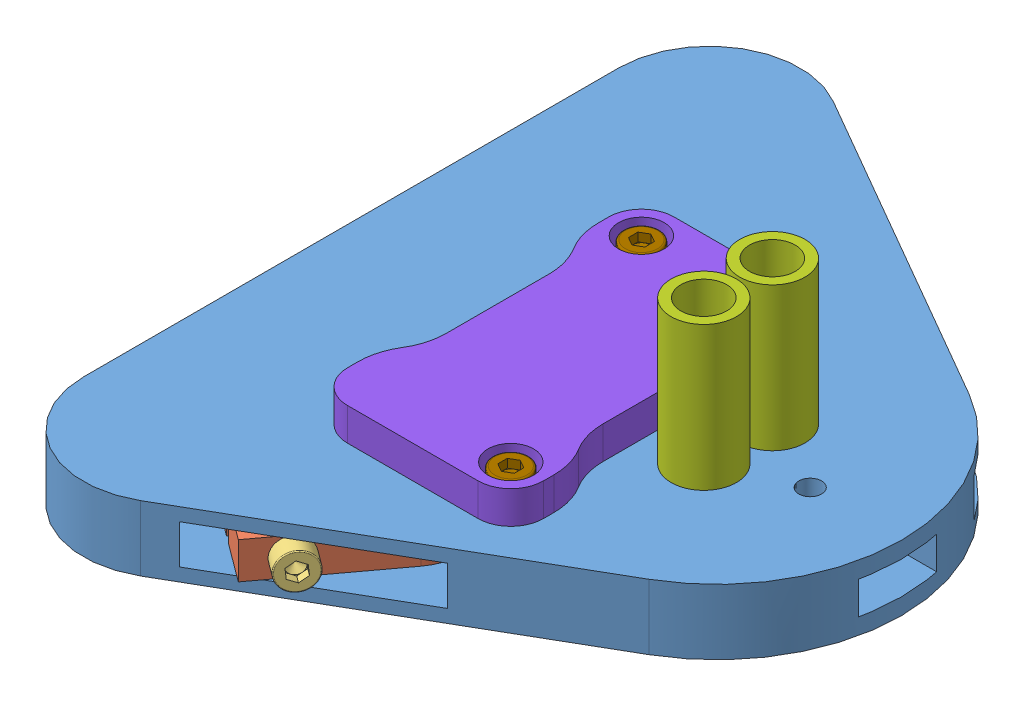
SolidWorks assembly PHeadAssembly, configuration Default. Lengths in mm.
Overall size (86.26 38.17 109.71).
26 component instances, 9 part files, 44 mates.
Components (placement in the parent):
- PHead-1: PHead [Default] at origin size (84.29 10 109.71)
- PRodFixAssembly-1: PRodFixAssembly [Default] at (15.0615 17.904 22.8104) x (-0.803549 0 -0.595239) z (-0.595239 0 0.803549) size (50.78 6 27.95)
  - PRodFix-1: PRodFix [Default] at (11.2747 15.304 14.188) size (15.9 5.6 27.95)
  - socket head cap screw_iso-2: socket head cap screw_iso [ISO 4762 M3 x 16 - 16N] at (0.3247 18.104 28.188) x (1 0 0) z (0 0.094972 0.99548) size (19 5.5 5.5)
  - hex nut style 1 gradeab_iso-3: hex nut style 1 gradeab_iso [ISO - 4032 - M3 - D - N] at (19.2247 18.104 28.188) x (0 -1 0) z (1 0 0) size (5.5 6.35 2.4)
- PRodFixAssembly-2: PRodFixAssembly [Default] at (46.5807 -17.904 -20.7975) x (-0.366111 0 0.930571) z (-0.930571 0 -0.366111) size (50.78 6 27.95)
  - PRodFix-1: PRodFix [Default] at (11.2747 15.304 14.188) size (15.9 5.6 27.95)
  - socket head cap screw_iso-2: socket head cap screw_iso [ISO 4762 M3 x 16 - 16N] at (0.3247 18.104 28.188) x (1 0 0) z (0 0.094972 0.99548) size (19 5.5 5.5)
  - hex nut style 1 gradeab_iso-3: hex nut style 1 gradeab_iso [ISO - 4032 - M3 - D - N] at (19.2247 18.104 28.188) x (0 -1 0) z (1 0 0) size (5.5 6.35 2.4)
- PRodFixAssembly-3: PRodFixAssembly [Default] at (-40.5758 -17.904 -32.9204) x (0.999782 0 0.02089) z (-0.02089 0 0.999782) size (50.78 6 27.95)
  - PRodFix-1: PRodFix [Default] at (11.2747 15.304 14.188) size (15.9 5.6 27.95)
  - socket head cap screw_iso-2: socket head cap screw_iso [ISO 4762 M3 x 16 - 16N] at (0.3247 18.104 28.188) x (1 0 0) z (0 0.094972 0.99548) size (19 5.5 5.5)
  - hex nut style 1 gradeab_iso-3: hex nut style 1 gradeab_iso [ISO - 4032 - M3 - D - N] at (19.2247 18.104 28.188) x (0 -1 0) z (1 0 0) size (5.5 6.35 2.4)
- _Riemenscheibe_GT2_20T-1: _Riemenscheibe_GT2_20T [Конфигурация1] at (0 0 -3.45) x (0 0 1) z (0.811645 0.584151 0) size (16 16 16)
- PHeadAchse-1: PHeadAchse [Default] at (0 0 -7.95) x (0 1 0) z (1 0 0) size (5 25 5)
- Kamerahalterung_Kabelführung_P-Kopf-1: Kamerahalterung_Kabelführung_P-Kopf [Standard] at (20 5 5) x (-0.29865 0 0.954363) z (-0.954363 0 -0.29865) size (10 22 10)
- hex nut style 1 gradeab_iso-2: hex nut style 1 gradeab_iso [ISO - 4032 - M3 - D - N] at (20 -4.9 5) x (0.5 0 -0.866025) z (0 -1 0) size (5.5 6.35 2.4)
- socket head cap screw_iso-1: socket head cap screw_iso [ISO 4762 M3 x 16 - 16N] at (20 12 5) x (0 -1 0) z (-0.5 0 -0.866025) size (19 5.5 5.5)
- Kamerahalterung_Kabelführung_P-Kopf-2: Kamerahalterung_Kabelführung_P-Kopf [Standard] at (20 5 -5.5) x (0 0 -1) z (1 0 0) size (10 22 10)
- hex nut style 1 gradeab_iso-3: hex nut style 1 gradeab_iso [ISO - 4032 - M3 - D - N] at (20 -4.9 -5.5) x (0.5 0 -0.866025) z (0 -1 0) size (5.5 6.35 2.4)
- socket head cap screw_iso-2: socket head cap screw_iso [ISO 4762 M3 x 16 - 16N] at (20 12 -5.5) x (0 -1 0) z (-0.5 0 -0.866025) size (19 5.5 5.5)
- PHead_Abdeckung_Gegenlager-1: PHead_Abdeckung_Gegenlager [Standard] at (0 5 4.55) x (0 0 -1) z (0 1 0) size (50 30 5)
- socket head cap screw 4762_din-1: socket head cap screw 4762_din [EN ISO 4762 M3 x 12 - 12N] at (10 9.5 24.55) x (0 -1 0) z (-0.5 0 -0.866025) size (15 5.5 5.5)
- hex nut style 1 gradeab_iso-4: hex nut style 1 gradeab_iso [ISO - 4032 - M3 - D - N] at (10 -2.5 24.55) x (1 0 0) z (0 1 0) size (5.5 6.35 2.4)
- socket head cap screw 4762_din-2: socket head cap screw 4762_din [EN ISO 4762 M3 x 12 - 12N] at (-10 9.5 -15.45) x (0 -1 0) z (-0.5 0 -0.866025) size (15 5.5 5.5)
- hex nut style 1 gradeab_iso-5: hex nut style 1 gradeab_iso [ISO - 4032 - M3 - D - N] at (-10 -2.5 -15.45) x (1 0 0) z (0 1 0) size (5.5 6.35 2.4)
Mates (geometry in assembly coordinates):
- Concentric1: concentric anti-aligned: cylinder of PHead-1 through (-2.4435 2 27.5) axis (0 -1 0) radius 4; cylinder of PRodFixAssembly-1/PRodFix-1 through (-2.4435 -3 27.5) axis (0 1 0) radius 4.05
- Concentric3: concentric aligned: circle of PHead-1; cylinder of PRodFixAssembly-2/PRodFix-1 through (29.25 3 -15.5) axis (0 -1 0) radius 4.05
- Coincident3: coincident anti-aligned: plane of PHead-1 through (29.25 3 -15.5) normal (0 -1 0); plane of PRodFixAssembly-2/PRodFix-1 through (29.25 3 -15.5) normal (0 1 0)
- Concentric4: concentric aligned: circle of PHead-1; cylinder of PRodFixAssembly-3/PRodFix-1 through (-29.6 3 -18.5) axis (0 -1 0) radius 4.05
- Coincident4: coincident anti-aligned: plane of PHead-1 through (-29.6 3 -18.5) normal (0 -1 0); plane of PRodFixAssembly-3/PRodFix-1 through (-29.6 3 -18.5) normal (0 1 0)
- Concentric5: concentric anti-aligned: cylinder of PHead-1 through (0 0 17.55) axis (0 0 -1) radius 2.5; cylinder of _Riemenscheibe_GT2_20T-1 through (0 0 -3.45) axis (0 0 1) radius 2.5
- Concentric6: concentric anti-aligned: cylinder of _Riemenscheibe_GT2_20T-1 through (0 0 -3.45) axis (0 0 1) radius 2.5; cylinder of PHeadAchse-1 through (0 0 17.05) axis (0 0 -1) radius 2.5
- Coincident6: distance = 0.5 mm anti-aligned: plane of PHead-1 through (0 5 -8.45) normal (0 0 1); plane of PHeadAchse-1 through (0 0 -7.95) normal (0 0 -1)
- Konzentrisch1: concentric anti-aligned: cylinder of PHead-1 through (20 -5 5) axis (0 1 0) radius 1.75; cylinder of Kamerahalterung_Kabelführung_P-Kopf-1 through (20 5 5) axis (0 -1 0) radius 1.75
- Deckungsgleich1: coincident anti-aligned: plane of PHead-1 through (0 5 0) normal (0 1 0); plane of Kamerahalterung_Kabelführung_P-Kopf-1 through (21.4932 5 0.2282) normal (0 -1 0)
- Konzentrisch2: concentric anti-aligned: cylinder of hex nut style 1 gradeab_iso-2 through (20 -2.5 5) axis (0 -1 0) radius 1.25; cylinder of socket head cap screw_iso-1 through (20 43.75 5) axis (0 1 0) radius 1.5
- Konzentrisch3: concentric anti-aligned: cylinder of hex nut style 1 gradeab_iso-2 through (20 -2.5 5) axis (0 -1 0) radius 1.25; cylinder of socket head cap screw_iso-1 through (20 43.75 5) axis (0 1 0) radius 1.5
- Parallel1: parallel aligned: plane of hex nut style 1 gradeab_iso-2 through (17.25 -2.5 6.5877) normal (-1 0 0); plane of socket head cap screw_iso-1 through (21.28 10.7 4.261) normal (-1 0 0)
- Konzentrisch4: concentric anti-aligned: cylinder of Kamerahalterung_Kabelführung_P-Kopf-1 through (20 5 5) axis (0 -1 0) radius 3.5; cylinder of socket head cap screw_iso-1 through (20 43.75 5) axis (0 1 0) radius 1.5
- Deckungsgleich3: coincident anti-aligned: plane of Kamerahalterung_Kabelführung_P-Kopf-1 through (20.5226 9 3.3299) normal (0 1 0); plane of socket head cap screw_iso-1 through (17.6184 9 6.375) normal (0 -1 0)
- Deckungsgleich4: coincident anti-aligned: plane of PHead-1 through (0 -2.5 0) normal (0 -1 0); plane of hex nut style 1 gradeab_iso-2 through (22.75 -2.5 6.5877) normal (0 1 0)
- Parallel2: parallel anti-aligned: plane of PHead-1 through (5.6651 -2.5 9.8122) normal (0.5 0 0.866025); plane of hex nut style 1 gradeab_iso-2 through (17.25 -2.5 3.4123) normal (-0.5 0 -0.866025)
- Konzentrisch5: concentric anti-aligned: cylinder of hex nut style 1 gradeab_iso-3 through (20 -2.5 -5.5) axis (0 -1 0) radius 1.25; cylinder of socket head cap screw_iso-2 through (20 43.75 -5.5) axis (0 1 0) radius 1.5
- Konzentrisch6: concentric anti-aligned: cylinder of hex nut style 1 gradeab_iso-3 through (20 -2.5 -5.5) axis (0 -1 0) radius 1.25; cylinder of socket head cap screw_iso-2 through (20 43.75 -5.5) axis (0 1 0) radius 1.5
- Parallel3: parallel aligned: plane of hex nut style 1 gradeab_iso-3 through (17.25 -2.5 -3.9123) normal (-1 0 0); plane of socket head cap screw_iso-2 through (21.28 10.7 -6.239) normal (-1 0 0)
- Konzentrisch7: concentric anti-aligned: cylinder of Kamerahalterung_Kabelführung_P-Kopf-2 through (20 5 -5.5) axis (0 -1 0) radius 3.5; cylinder of socket head cap screw_iso-2 through (20 43.75 -5.5) axis (0 1 0) radius 1.5
- Deckungsgleich6: coincident anti-aligned: plane of Kamerahalterung_Kabelführung_P-Kopf-2 through (20 9 -3.75) normal (0 1 0); plane of socket head cap screw_iso-2 through (17.6184 9 -4.125) normal (0 -1 0)
- Deckungsgleich7: coincident anti-aligned: plane of PHead-1 through (0 5 0) normal (0 1 0); plane of Kamerahalterung_Kabelführung_P-Kopf-2 through (20 5 -0.5) normal (0 -1 0)
- Deckungsgleich8: coincident anti-aligned: plane of PHead-1 through (0 -2.5 0) normal (0 -1 0); plane of hex nut style 1 gradeab_iso-3 through (22.75 -2.5 -3.9123) normal (0 1 0)
- Parallel4: parallel anti-aligned: plane of PHead-1 through (5.6651 -2.5 9.8122) normal (0.5 0 0.866025); plane of hex nut style 1 gradeab_iso-3 through (17.25 -2.5 -7.0877) normal (-0.5 0 -0.866025)
- Abstand1: distance = 1.5 mm: cylinder of Kamerahalterung_Kabelführung_P-Kopf-2 through (20 5 -5.5) axis (0 -1 0) radius 3.5; cylinder of PHead-1 through (20 -5 -4) axis (0 1 0) radius 1.75
- Deckungsgleich13: coincident aligned: plane of PHead-1 through (20 0 0) normal (1 0 0); plane of Kamerahalterung_Kabelführung_P-Kopf-2 through (20 5 -5.5) normal (1 0 0)
- Coincident7: coincident anti-aligned: plane of PHead-1 through (-2.4435 -3 27.5) normal (0 1 0); plane of PRodFixAssembly-1/PRodFix-1 through (-2.4435 -3 27.5) normal (0 -1 0)
- Distance1: distance = 1 mm anti-aligned: plane of PHead-1 through (0 -5 -4.45) normal (0 0 1); plane of _Riemenscheibe_GT2_20T-1 through (0 0 -3.45) normal (0 0 -1)
- Deckungsgleich14: coincident anti-aligned: plane of PHead-1 through (0 5 0) normal (0 1 0); plane of PHead_Abdeckung_Gegenlager-1 through (0 5 4.55) normal (0 -1 0)
- Konzentrisch8: concentric aligned: cylinder of PHead-1 through (-10 -5 -15.45) axis (0 1 0) radius 1.75; cylinder of PHead_Abdeckung_Gegenlager-1 through (-10 5 -15.45) axis (0 1 0) radius 1.75
- Konzentrisch9: concentric aligned: cylinder of PHead-1 through (10 -5 24.55) axis (0 1 0) radius 1.75; cylinder of PHead_Abdeckung_Gegenlager-1 through (10 5 24.55) axis (0 1 0) radius 1.75
- Konzentrisch10: concentric aligned: cylinder of PHead_Abdeckung_Gegenlager-1 through (10 5 24.55) axis (0 1 0) radius 1.75; cylinder of socket head cap screw 4762_din-1 through (10 41.25 24.55) axis (0 1 0) radius 1.5
- Deckungsgleich2: coincident anti-aligned: plane of PHead_Abdeckung_Gegenlager-1 through (10 6.5 24.55) normal (0 1 0); plane of socket head cap screw 4762_din-1 through (7.6184 6.5 25.925) normal (0 -1 0)
- Konzentrisch11: concentric aligned: cylinder of PHead_Abdeckung_Gegenlager-1 through (-10 5 -15.45) axis (0 1 0) radius 1.75; cylinder of socket head cap screw 4762_din-2 through (-10 41.25 -15.45) axis (0 1 0) radius 1.5
- Deckungsgleich15: coincident anti-aligned: plane of PHead_Abdeckung_Gegenlager-1 through (-10 6.5 -15.45) normal (0 1 0); plane of socket head cap screw 4762_din-2 through (-12.3816 6.5 -14.075) normal (0 -1 0)
- Konzentrisch12: concentric aligned: cylinder of socket head cap screw 4762_din-1 through (10 41.25 24.55) axis (0 1 0) radius 1.5; cylinder of hex nut style 1 gradeab_iso-4 through (10 -4.9 24.55) axis (0 1 0) radius 1.25
- Parallel5: parallel aligned: plane of socket head cap screw 4762_din-1 through (10 8.2 23.0951) normal (-0.5 0 0.866025); plane of hex nut style 1 gradeab_iso-4 through (7.25 -4.9 26.1377) normal (-0.5 0 0.866025)
- Parallel6: parallel aligned: plane of PHead-1 through (10 -2.5 21.0859) normal (0.5 0 0.866025); plane of hex nut style 1 gradeab_iso-4 through (10 -4.9 27.7254) normal (0.5 0 0.866025)
- Deckungsgleich16: coincident anti-aligned: plane of PHead-1 through (0 -2.5 0) normal (0 -1 0); plane of hex nut style 1 gradeab_iso-4 through (10 -2.5 21.3746) normal (0 1 0)
- Konzentrisch13: concentric aligned: cylinder of socket head cap screw 4762_din-2 through (-10 41.25 -15.45) axis (0 1 0) radius 1.5; cylinder of hex nut style 1 gradeab_iso-5 through (-10 -4.9 -15.45) axis (0 1 0) radius 1.25
- Parallel7: parallel aligned: plane of socket head cap screw 4762_din-2 through (-10 8.2 -16.9049) normal (-0.5 0 0.866025); plane of hex nut style 1 gradeab_iso-5 through (-12.75 -4.9 -13.8623) normal (-0.5 0 0.866025)
- Parallel8: parallel aligned: plane of PHead-1 through (10 -2.5 21.0859) normal (0.5 0 0.866025); plane of hex nut style 1 gradeab_iso-5 through (-10 -4.9 -12.2746) normal (0.5 0 0.866025)
- Deckungsgleich17: coincident anti-aligned: plane of PHead-1 through (0 -2.5 0) normal (0 -1 0); plane of hex nut style 1 gradeab_iso-5 through (-10 -2.5 -18.6254) normal (0 1 0)
